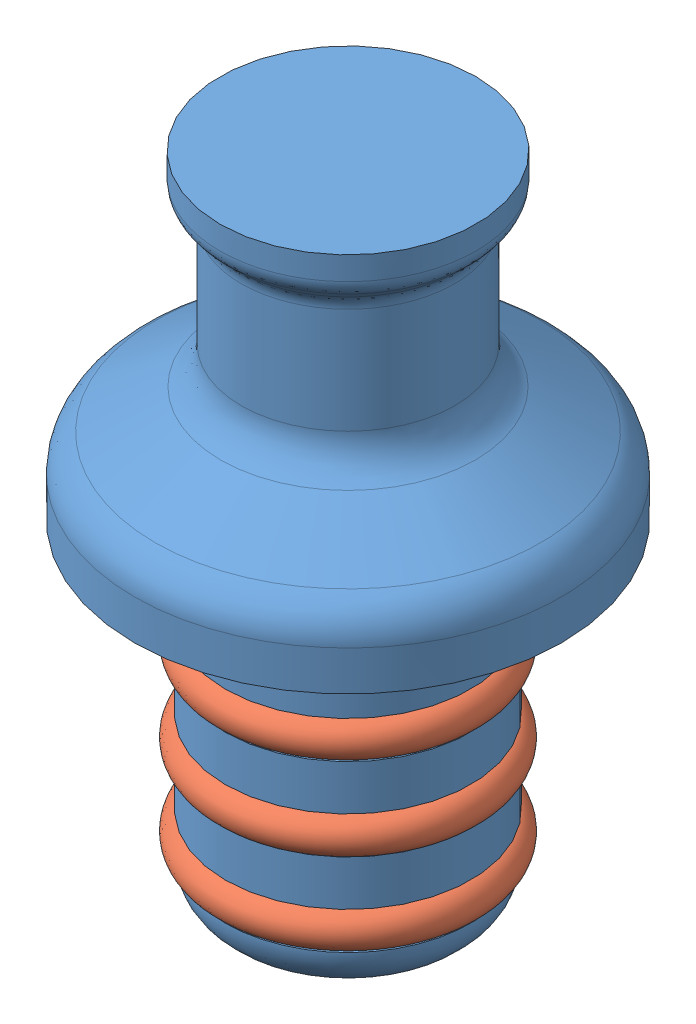
SolidWorks assembly Normbuchse-Stopfen, configuration Standard. Lengths in mm.
Overall size (20 30.5 20).
5 component instances, 3 part files, 8 mates.
Components (placement in the parent):
- Normbuchse-Stopfen-1: Normbuchse-Stopfen [Standard] at (-113.3021 -10.0814 0) size (20 30.5 20)
- O-Ring-12mm-1: O-Ring-12mm [Standard] at (-113.3021 0.5436 0) x (0.999693 0 -0.024773) z (0 -1 0) size (12.5 12.5 1.75)
- O-Ring-15mm-1: O-Ring-15mm [Standard] at (-113.3021 5.9186 0) x (1 0 0) z (0 -1 0) size (14.5 14.5 2)
- O-Ring-12mm-2: O-Ring-12mm [Standard] at (-113.3021 -3.3814 0) x (0.998627 0 -0.05238) z (0 -1 0) size (12.5 12.5 1.75)
- O-Ring-12mm-3: O-Ring-12mm [Standard] at (-113.3021 -7.2064 0) x (-0.982926 0 0.184002) z (0 -1 0) size (12.5 12.5 1.75)
Mates (geometry in assembly coordinates):
- Konzentrisch1: concentric anti-aligned: circle of Normbuchse-Stopfen-1; line of O-Ring-12mm-3 through (-113.3021 -7.2064 0) axis (0 1 0)
- Abstand1: distance = 2.875 mm: point of O-Ring-12mm-3; plane of Normbuchse-Stopfen-1 through (-113.3021 -10.0814 0) normal (0 -1 0)
- Konzentrisch2: concentric anti-aligned: circle of Normbuchse-Stopfen-1; line of O-Ring-12mm-2 through (-113.3021 -3.3814 0) axis (0 1 0)
- Konzentrisch3: concentric anti-aligned: circle of Normbuchse-Stopfen-1; line of O-Ring-12mm-1 through (-113.3021 0.5436 0) axis (0 1 0)
- Abstand2: distance = 10.625 mm: point of O-Ring-12mm-1; plane of Normbuchse-Stopfen-1 through (-113.3021 -10.0814 0) normal (0 -1 0)
- Abstand3: distance = 6.7 mm: point of O-Ring-12mm-2; plane of Normbuchse-Stopfen-1 through (-113.3021 -10.0814 0) normal (0 -1 0)
- Konzentrisch4: concentric anti-aligned: circle of Normbuchse-Stopfen-1; line of O-Ring-15mm-1 through (-113.3021 5.9186 0) axis (0 1 0)
- Abstand4: distance = 16 mm: point of O-Ring-15mm-1; plane of Normbuchse-Stopfen-1 through (-113.3021 -10.0814 0) normal (0 -1 0)
